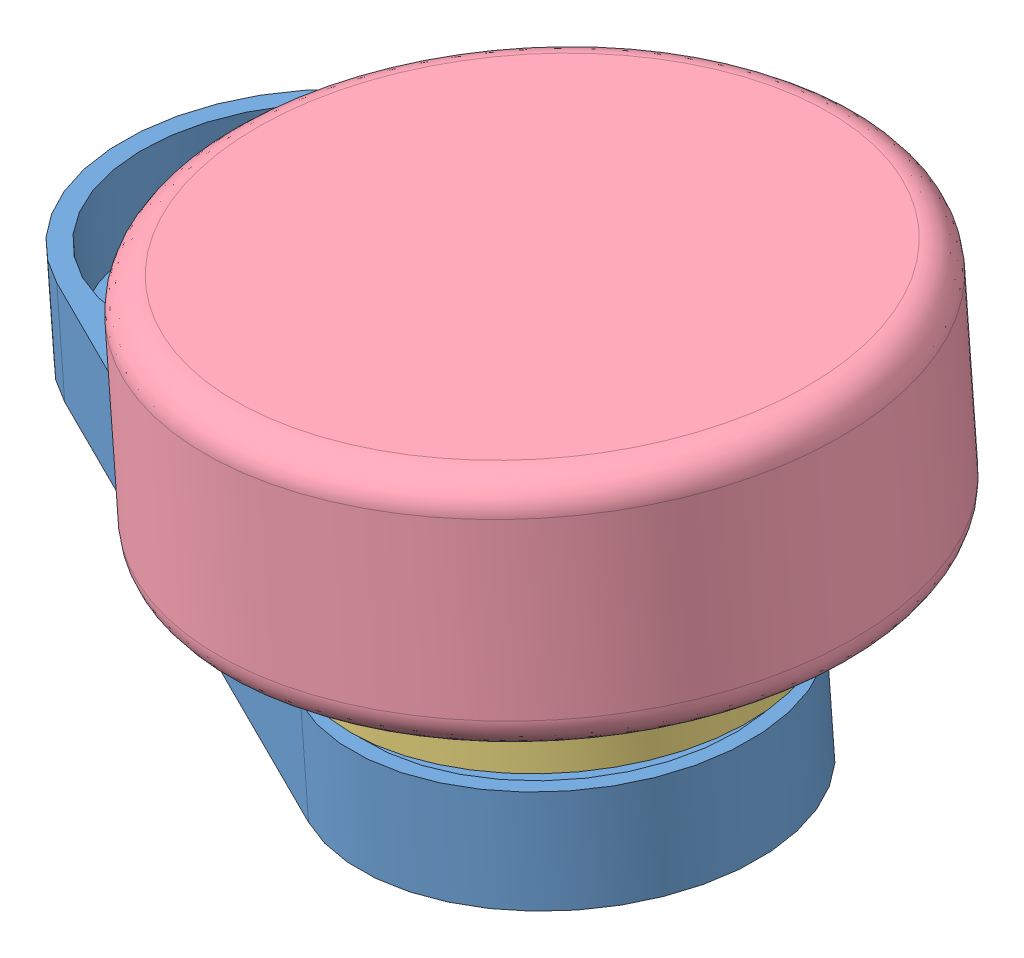
SolidWorks assembly 小腿总成, configuration 默认. Lengths in mm.
Overall size (158.96 77.76 128.3).
9 component instances, 6 part files, 12 mates.
Components (placement in the parent):
- 小腿-1: 小腿 [默认] at (76.3306 -73.6133 142.6505) x (-0.47446 -0.035633 0.879555) z (0.085914 -0.996285 0.005983) size (50 130 21)
- m3x25铜柱-1: m3x25铜柱 [默认] at (117.777 -59.9941 143.958) x (-0.780619 -0.063582 0.621765) z (0.085914 -0.996285 0.005983) size (5.01 5.03 15)
- m3x25铜柱-2: m3x25铜柱 [默认] at (99.7475 -61.3481 177.3811) x (-0.780619 -0.063582 0.621765) z (0.085914 -0.996285 0.005983) size (5.01 5.03 15)
- m3x25铜柱-3: m3x25铜柱 [默认] at (139.6789 -58.0339 155.8519) x (-0.780619 -0.063582 0.621765) z (0.085914 -0.996285 0.005983) size (5.01 5.03 15)
- m3x25铜柱-4: m3x25铜柱 [默认] at (121.6494 -59.388 189.275) x (-0.780619 -0.063582 0.621765) z (0.085914 -0.996285 0.005983) size (5.01 5.03 15)
- 小腿电机-1: 小腿电机 [默认] at (145.2997 -54.3892 180.6334) x (-0.47446 -0.035633 0.879555) z (0.085914 -0.996285 0.005983) size (50 80 14)
- 轮子-1: 轮子 [默认] at (144.8701 -49.4078 180.6035) x (0.654824 0.060993 0.753316) z (-0.085914 0.996285 -0.005983) size (80 80 30)
- 电机座-1: 电机座 [默认] at (125.6262 -59.2028 163.0043) x (-0.47446 -0.035633 0.879555) z (0.876074 0.078405 0.475759) size (22.8 11.5 11.5)
- 电机-1: 电机 [默认] at (122.5302 -69.369 160.9223) x (0.876074 0.078405 0.475759) z (-0.47446 -0.035633 0.879555) size (39 28.5 12)
Mates (geometry in assembly coordinates):
- 重合17: coincident anti-aligned: circle of 小腿-1; circle of m3x25铜柱-1
- 重合18: coincident aligned: circle of m3x25铜柱-2; circle of 小腿电机-1
- 同心20: concentric anti-aligned: circle of 小腿-1; circle of 小腿电机-1
- 同心21: concentric anti-aligned: circle of 小腿电机-1; circle of 轮子-1
- 距离1: distance = 5 mm anti-aligned: plane of 小腿电机-1 through (145.2997 -54.3892 180.6334) normal (-0.085914 0.996285 -0.005983); plane of 轮子-1 through (144.8701 -49.4078 180.6035) normal (0.085914 -0.996285 0.005983)
- 平行1: parallel anti-aligned: plane of 小腿-1 through (76.7602 -78.5948 142.6804) normal (-0.085914 0.996285 -0.005983); plane of m3x25铜柱-1 through (119.0657 -74.9383 144.0477) normal (0.085914 -0.996285 0.005983)
- 重合21: coincident anti-aligned: plane of 电机座-1 through (135.7011 -58.3012 168.4756) normal (0.876074 0.078405 0.475759); plane of 电机-1 through (136.5473 -68.1146 168.5345) normal (-0.876074 -0.078405 -0.475759)
- 重合24: coincident anti-aligned: plane of 电机座-1 through (136.5473 -68.1146 168.5345) normal (-0.085914 0.996285 -0.005983); plane of 电机-1 through (116.8366 -69.7966 171.477) normal (0.085914 -0.996285 0.005983)
- 重合25: coincident anti-aligned: plane of 电机座-1 through (135.7011 -58.3012 168.4756) normal (-0.47446 -0.035633 0.879555); plane of 电机-1 through (122.5302 -69.369 160.9223) normal (0.47446 0.035633 -0.879555)
- 同心22: concentric anti-aligned: circle of 小腿电机-1; circle of 电机-1
- 重合26: coincident anti-aligned: plane of 小腿电机-1 through (145.5574 -57.3781 180.6514) normal (0.085914 -0.996285 0.005983); plane of 电机座-1 through (138.3106 -58.1052 163.638) normal (-0.085914 0.996285 -0.005983)
- 平行2: parallel aligned: plane of 小腿电机-1 through (101.7537 -61.2983 156.8634) normal (-0.876074 -0.078405 -0.475759); plane of 电机-1 through (116.8366 -69.7966 171.477) normal (-0.876074 -0.078405 -0.475759)
